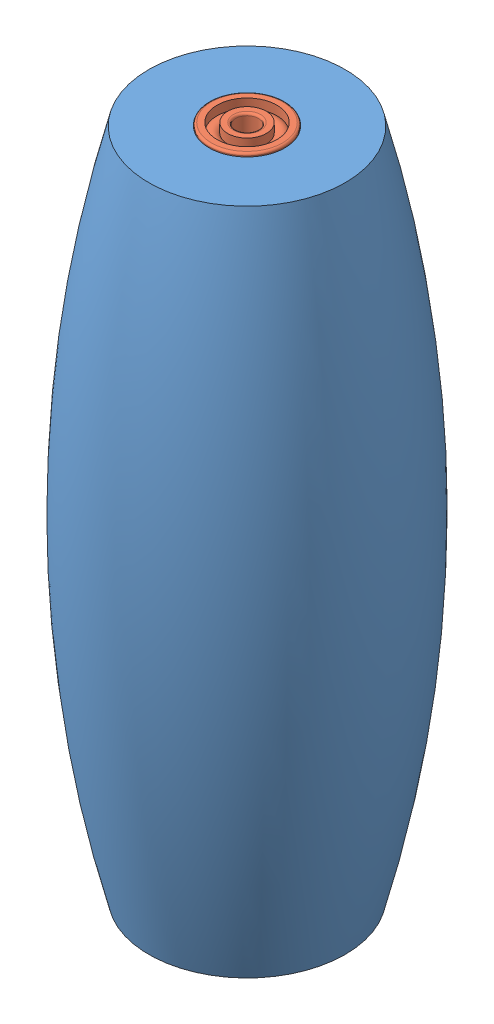
SolidWorks assembly satellitewheel_assembly_2, configuration Default. Lengths in mm.
Overall size (550.8 76.63 18.72).
4 component instances, 3 part files, 7 mates.
Components (placement in the parent):
- Satellite Wheel-1: Satellite Wheel [Default] at (-230.7088 -10.4586 -3.6611) size (550.8 71.36 18.72)
- instrument ball bearing_68_am-1: instrument ball bearing_68_am [AFBMA 12.1.4.1 - 0015-5 - 8,SI,NC,8_68] at (-249.7985 1.4263 -3.6611) x (0 1 0) z (0.469874 0 0.882734) size (2 5 5)
- instrument ball bearing_68_am-3: instrument ball bearing_68_am [AFBMA 12.1.4.1 - 0015-5 - 8,SI,NC,8_68] at (-249.7985 -41.1817 -3.6611) x (0 -1 0) z (0.579803 0 0.814757) size (2 5 5)
- wheelshaft-1: wheelshaft [Default] at (-249.7985 1.7223 -3.6611) x (-0.300283 0 0.95385) z (0 -1 0) size (2.35 2.35 54.72)
Mates (geometry in assembly coordinates):
- Concentric1: concentric aligned: cylinder of Satellite Wheel-1 through (-249.7985 0.4263 -3.6611) axis (0 1 0) radius 2.35; cylinder of instrument ball bearing_68_am-1 through (-249.7985 -19.2112 -3.6611) axis (0 1 0) radius 0.75
- Concentric2: concentric aligned: cylinder of instrument ball bearing_68_am-1 through (-249.7985 -19.2112 -3.6611) axis (0 1 0) radius 2.5; cylinder of ? through (-249.7985 -14.4053 -3.6611) axis (0 1 0) radius 0.75
- Concentric3: concentric aligned: cylinder of Satellite Wheel-1 through (-249.7985 -40.1817 -3.6611) axis (0 -1 0) radius 2.35; cylinder of instrument ball bearing_68_am-3 through (-249.7985 -20.5442 -3.6611) axis (0 -1 0) radius 0.75
- Coincident2: coincident anti-aligned: plane of Satellite Wheel-1 through (-249.7985 -40.1817 -3.6611) normal (0 -1 0); plane of instrument ball bearing_68_am-3 through (-248.1893 -40.1817 -4.8062) normal (0 1 0)
- Coincident3: coincident anti-aligned: plane of Satellite Wheel-1 through (-249.7985 0.4263 -3.6611) normal (0 1 0); plane of instrument ball bearing_68_am-1 through (-251.5419 0.4263 -2.7331) normal (0 -1 0)
- Concentric4: concentric anti-aligned: cylinder of instrument ball bearing_68_am-3 through (-249.7985 -20.5442 -3.6611) axis (0 -1 0) radius 0.75; cylinder of wheelshaft-1 through (-249.7985 -47.2317 -3.6611) axis (0 1 0) radius 0.705
- Width1: width anti-aligned: plane of wheelshaft-1 through (-249.7985 -47.2317 -3.6611) normal (0 -1 0); plane of wheelshaft-1 through (-249.7985 7.4763 -3.6611) normal (0 1 0); plane of Satellite Wheel-1 through (-231.8542 2.2123 -3.6611) normal (0 1 0); plane of Satellite Wheel-1 through (-231.8542 -41.9677 -3.6611) normal (0 -1 0)
